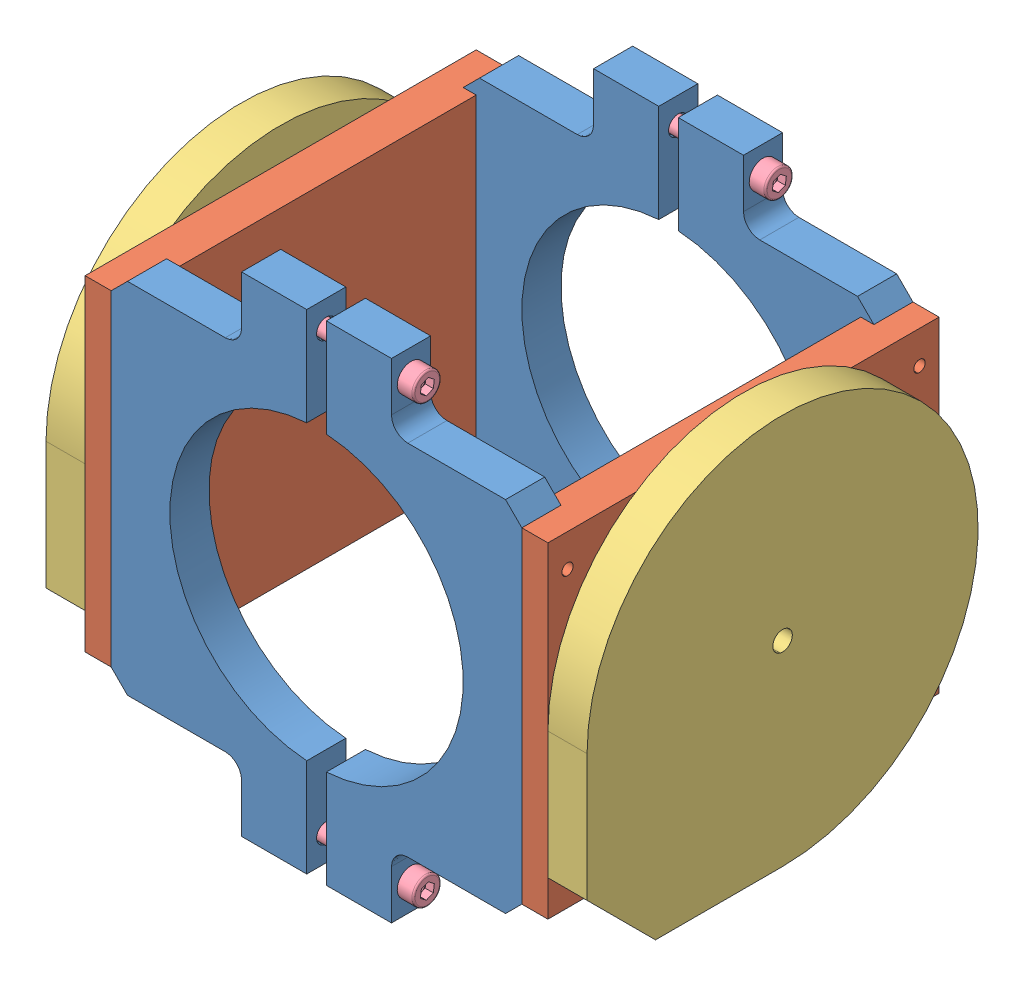
SolidWorks assembly TubeClamp, configuration Default. Lengths in mm.
Overall size (166 150 120).
12 component instances, 4 part files, 29 mates.
Components (placement in the parent):
- TubeClampTop-1: TubeClampTop [Default] at (-55.1494 74.5482 136.7463) size (60 150 12)
- TubeClampSide-1: TubeClampSide [Default] at (72.8506 74.5482 190.7463) x (0 0 1) z (-1 0 0) size (120 100 12)
- TubeClampSide-2: TubeClampSide [Default] at (-57.1494 74.5482 190.7463) x (0 0 1) z (1 0 0) size (120 100 12)
- TubeClampTop-2: TubeClampTop [Default] at (-55.1494 74.5482 244.7463) x (1 0 0) z (0 0 -1) size (60 150 12)
- TubeClampDisk-1: TubeClampDisk [Default] at (-69.1494 74.5482 190.7463) x (0 1 0) z (1 0 0) size (120 120 12)
- TubeClampDisk-2: TubeClampDisk [Default] at (84.8506 74.5482 190.7463) x (0 1 0) z (1 0 0) size (120 120 12)
- TubeClampTop-3: TubeClampTop [Default] at (70.8506 74.5482 136.7463) x (-1 0 0) z (0 0 1) size (60 150 12)
- TubeClampTop-4: TubeClampTop [Default] at (70.8506 74.5482 244.7463) x (-1 0 0) z (0 0 1) size (60 150 12)
- socket head cap screw_din-3: socket head cap screw_din [DIN 912 M5 x 50 --- 22N] at (35.8506 141.5482 244.7463) x (-1 0 0) z (0 0.924225 0.381849) size (55 8.5 8.5)
- socket head cap screw_din-4: socket head cap screw_din [DIN 912 M5 x 50 --- 22N] at (35.8506 141.5482 136.7463) x (-1 0 0) z (0 0.924225 0.381849) size (55 8.5 8.5)
- socket head cap screw_din-5: socket head cap screw_din [DIN 912 M5 x 50 --- 22N] at (35.8506 7.5482 136.7463) x (-1 0 0) z (0 0.924225 0.381849) size (55 8.5 8.5)
- socket head cap screw_din-6: socket head cap screw_din [DIN 912 M5 x 50 --- 22N] at (35.8506 7.5482 244.7463) x (-1 0 0) z (0 0.924225 0.381849) size (55 8.5 8.5)
Mates (geometry in assembly coordinates):
- Concentric1: concentric anti-aligned: cylinder of TubeClampSide-2 through (-63.1504 74.5482 190.7463) axis (1 0 0) radius 3; cylinder of TubeClampDisk-1 through (-63.1494 74.5482 190.7463) axis (-1 0 0) radius 60
- Coincident10: coincident anti-aligned: plane of TubeClampSide-2 through (-63.1494 74.5482 190.7463) normal (-1 0 0); plane of TubeClampDisk-1 through (-63.1494 74.5482 190.7463) normal (1 0 0)
- Coincident14: coincident aligned: plane of TubeClampSide-2 through (-51.1494 24.5482 250.7463) normal (0 0 1); plane of TubeClampTop-2 through (7.8506 74.5482 250.7463) normal (0 0 1)
- Coincident15: coincident anti-aligned: plane of TubeClampTop-1 through (-55.1494 19.5482 142.7463) normal (-1 0 0); plane of TubeClampSide-2 through (-55.1494 74.5482 190.7463) normal (1 0 0)
- Coincident16: coincident aligned: line of TubeClampTop-1 through (-55.1494 24.5482 130.7463) axis (0 0 1); plane of TubeClampSide-2 through (-51.1494 24.5482 130.7463) normal (0 -1 0)
- Coincident17: coincident aligned: plane of TubeClampTop-1 through (7.8506 74.5482 130.7463) normal (0 0 -1); plane of TubeClampSide-2 through (-51.1494 24.5482 130.7463) normal (0 0 -1)
- Concentric3: concentric anti-aligned: cylinder of TubeClampTop-2 through (-55.1504 7.5482 244.7463) axis (1 0 0) radius 3; cylinder of TubeClampTop-4 through (70.8516 7.5482 244.7463) axis (-1 0 0) radius 3
- Concentric4: concentric anti-aligned: cylinder of TubeClampTop-2 through (-55.1504 141.5482 244.7463) axis (1 0 0) radius 3; cylinder of TubeClampTop-4 through (70.8516 141.5482 244.7463) axis (-1 0 0) radius 3
- Concentric5: concentric anti-aligned: cylinder of TubeClampTop-1 through (-55.1504 141.5482 136.7463) axis (1 0 0) radius 3; cylinder of TubeClampTop-3 through (70.8516 141.5482 136.7463) axis (-1 0 0) radius 3
- Concentric6: concentric anti-aligned: cylinder of TubeClampTop-1 through (-55.1504 7.5482 136.7463) axis (1 0 0) radius 3; cylinder of TubeClampTop-3 through (70.8516 7.5482 136.7463) axis (-1 0 0) radius 3
- Concentric10: concentric anti-aligned: cylinder of TubeClampTop-4 through (70.8516 141.5482 244.7463) axis (-1 0 0) radius 3; cylinder of socket head cap screw_din-3 through (67.6006 141.5482 244.7463) axis (1 0 0) radius 4.25
- Coincident25: coincident anti-aligned: plane of TubeClampTop-4 through (30.8506 129.5482 250.7463) normal (1 0 0); plane of socket head cap screw_din-3 through (30.8506 139.9254 248.6743) normal (-1 0 0)
- Concentric11: concentric anti-aligned: cylinder of TubeClampTop-3 through (70.8516 141.5482 136.7463) axis (-1 0 0) radius 3; cylinder of socket head cap screw_din-4 through (67.6006 141.5482 136.7463) axis (1 0 0) radius 4.25
- Coincident26: coincident anti-aligned: plane of TubeClampTop-3 through (30.8506 129.5482 142.7463) normal (1 0 0); plane of socket head cap screw_din-4 through (30.8506 139.9254 140.6743) normal (-1 0 0)
- Concentric12: concentric anti-aligned: cylinder of TubeClampTop-3 through (70.8516 7.5482 136.7463) axis (-1 0 0) radius 3; cylinder of socket head cap screw_din-5 through (67.6006 7.5482 136.7463) axis (1 0 0) radius 4.25
- Coincident27: coincident anti-aligned: plane of TubeClampTop-3 through (30.8506 19.5482 142.7463) normal (1 0 0); plane of socket head cap screw_din-5 through (30.8506 5.9254 140.6743) normal (-1 0 0)
- Concentric13: concentric anti-aligned: cylinder of TubeClampTop-4 through (70.8516 7.5482 244.7463) axis (-1 0 0) radius 3; cylinder of socket head cap screw_din-6 through (67.6006 7.5482 244.7463) axis (1 0 0) radius 4.25
- Coincident28: coincident anti-aligned: plane of TubeClampTop-4 through (30.8506 19.5482 250.7463) normal (1 0 0); plane of socket head cap screw_din-6 through (30.8506 5.9254 248.6743) normal (-1 0 0)
- Coincident29: coincident anti-aligned: plane of TubeClampSide-1 through (78.8506 74.5482 190.7463) normal (1 0 0); plane of TubeClampDisk-2 through (78.8506 74.5482 190.7463) normal (-1 0 0)
- Concentric14: concentric aligned: cylinder of TubeClampSide-1 through (78.8516 74.5482 190.7463) axis (-1 0 0) radius 3; cylinder of TubeClampDisk-2 through (90.8506 74.5482 190.7463) axis (-1 0 0) radius 3
- Coincident30: coincident anti-aligned: plane of TubeClampSide-1 through (70.8506 74.5482 190.7463) normal (-1 0 0); plane of TubeClampTop-3 through (70.8506 129.5482 142.7463) normal (1 0 0)
- Coincident31: coincident anti-aligned: plane of TubeClampSide-1 through (70.8506 124.5482 142.7463) normal (0 0 -1); plane of TubeClampTop-3 through (7.8506 74.5482 142.7463) normal (0 0 1)
- Coincident32: coincident: plane of TubeClampSide-1 through (66.8506 124.5482 130.7463) normal (0 1 0); line of TubeClampTop-3 through (70.8506 124.5482 130.7463) axis (0 0 1)
- Coincident33: coincident anti-aligned: plane of TubeClampSide-2 through (-55.1494 74.5482 190.7463) normal (1 0 0); plane of TubeClampTop-2 through (-55.1494 129.5482 238.7463) normal (-1 0 0)
- Coincident34: coincident: plane of TubeClampSide-1 through (66.8506 124.5482 130.7463) normal (0 1 0); line of TubeClampTop-4 through (70.8506 124.5482 238.7463) axis (0 0 1)
- Distance1: distance = 6 mm anti-aligned: plane of TubeClampTop-1 through (4.8506 149.5482 142.7463) normal (1 0 0); plane of TubeClampTop-3 through (10.8506 149.5482 142.7463) normal (-1 0 0)
- Coincident36: coincident anti-aligned: plane of TubeClampSide-1 through (70.8506 74.5482 190.7463) normal (-1 0 0); plane of TubeClampTop-4 through (70.8506 129.5482 250.7463) normal (1 0 0)
- Coincident37: coincident aligned: plane of TubeClampSide-1 through (66.8506 124.5482 250.7463) normal (0 0 1); plane of TubeClampDisk-2 through (175.7034 74.5482 250.7463) normal (0 0 1)
- Coincident38: coincident aligned: plane of TubeClampSide-2 through (-51.1494 24.5482 250.7463) normal (0 0 1); plane of TubeClampDisk-1 through (21.7034 74.5482 250.7463) normal (0 0 1)
